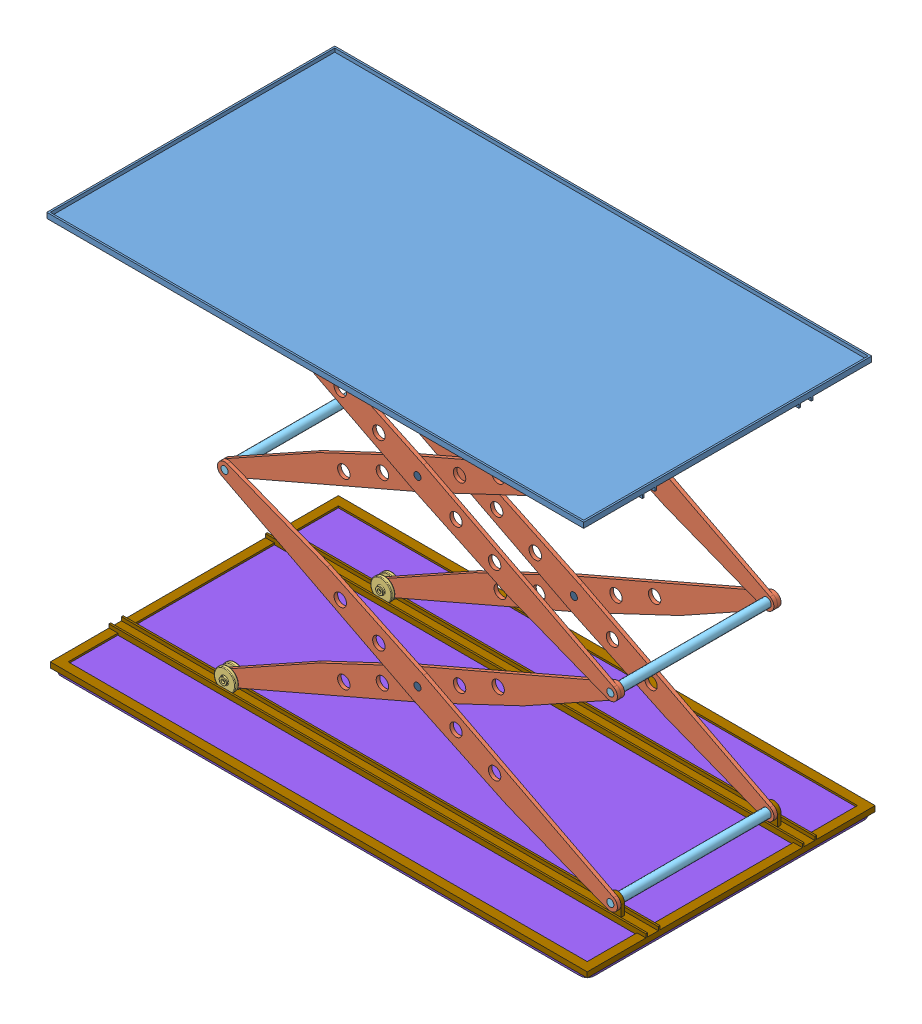
SolidWorks assembly Lift, configuration Default. Lengths in mm.
Overall size (1524.62 1125.01 820).
26 component instances, 10 part files, 62 mates.
Components (placement in the parent):
- Ground Frame-1: Ground Frame [Default] at (6.645 35.4607 -1636.1522) size (1510 70 810)
- Scissor Arm-1: Scissor Arm [Default] at (114.1185 -255.7912 -1846.1522) x (0.904211 0.427086 0) z (0 0 1) size (1240 80 10)
- Scissor Arm-3: Scissor Arm [Default] at (114.1185 -255.7912 -1426.1522) x (0.904211 0.427086 0) z (0 0 1) size (1240 80 10)
- Scissor Arm-4: Scissor Arm [Default] at (114.1185 -255.7912 -1856.1522) x (0.904211 -0.427086 0) z (0 0 1) size (1240 80 10)
- Scissor Arm-5: Scissor Arm [Default] at (114.1185 -255.7912 -1416.1522) x (0.904211 -0.427086 0) z (0 0 1) size (1240 80 10)
- Roller-1: Roller [Default] at (-428.408 0.4607 -1871.1522) x (-0.996904 0.078629 0) z (0 0 1) size (60 60 40)
- Roller-2: Roller [Default] at (-428.408 0.4607 -1431.1522) x (0.925109 -0.379702 0) z (0 0 1) size (60 60 40)
- Force Rod-2: Force Rod [Default] at (-428.408 0.4607 -1636.1522) x (0 0 1) z (-1 0 0) size (410 40 30)
- Scissor Arm-6: Scissor Arm [Default] at (114.1185 -768.2949 -1856.1522) x (0.904211 -0.427086 0) z (0 0 1) size (1240 80 10)
- Scissor Arm-7: Scissor Arm [Default] at (114.1185 -768.2949 -1416.1522) x (0.904211 -0.427086 0) z (0 0 1) size (1240 80 10)
- Scissor Arm-8: Scissor Arm [Default] at (114.1185 -768.2949 -1426.1522) x (0.904211 0.427086 0) z (0 0 1) size (1240 80 10)
- Scissor Arm-9: Scissor Arm [Default] at (114.1185 -768.2949 -1866.1522) x (0.904211 0.427086 0) z (0 0 1) size (1240 80 10)
- Center Rod-1: Center Rod [Default] at (656.645 -512.0431 -1641.1522) x (0 0 1) z (0.968151 -0.250368 0) size (460 25 25)
- Center Rod-2: Center Rod [Default] at (656.645 0.4607 -1641.1522) x (0 0 -1) z (0.999908 0.013578 0) size (460 25 25)
- Center Rod-3: Center Rod [Default] at (-428.408 -512.0431 -1641.1522) x (0 0 1) z (-0.996451 -0.084176 0) size (460 25 25)
- Lead Screw-1: Lead Screw [Default] at (-247.9541 0.4607 -1636.1522) x (1 0 0) z (0 -0.731326 0.682028) size (1030.02 30.61 26.52)
- Motor-1: Motor [Default] at (322.1358 0.4607 -1615.8755) x (0 0 1) z (-1 0 0) size (60 60 90)
- Platform-1: Platform [Default] at (6.645 -1069.5468 -1646.1522) size (1500 20 800)
- Frame-1: Frame [Default] at (6.645 -1059.5468 -1646.1522) x (1 0 0) z (0 0 -1) size (1510 65 810)
- Center Rod-4: Center Rod [Default] at (656.645 -1024.5468 -1641.1522) x (0 0 1) z (0.247233 0.968956 0) size (460 25 25)
- Roller-3: Roller [Default] at (-428.408 -1024.5468 -1881.1522) size (60 60 40)
- Roller-4: Roller [Default] at (-428.408 -1024.5468 -1441.1522) x (0.838333 0.545159 0) z (0 0 1) size (60 60 40)
- fixingCenter-1: fixingCenter [Default] at (114.1185 -255.7912 -1856.1522) x (0 0 -1) z (0.990959 0.134167 0) size (30 25 25)
- fixingCenter-2: fixingCenter [Default] at (114.1185 -255.7912 -1426.1522) x (0 0 -1) z (0.998189 0.060154 0) size (30 25 25)
- fixingCenter-3: fixingCenter [Default] at (114.1185 -768.2949 -1426.1522) x (0 0 -1) z (1 0 0) size (30 25 25)
- fixingCenter-4: fixingCenter [Default] at (114.1185 -768.2949 -1866.1522) x (0 0 -1) z (0.935797 0.352539 0) size (30 25 25)
Mates (geometry in assembly coordinates):
- Concentric1: concentric aligned: cylinder of Ground Frame-1 through (656.645 0.4607 -1851.1522) axis (0 0 -1) radius 10; cylinder of Scissor Arm-1 through (656.645 0.4607 -1841.1522) axis (0 0 -1) radius 10
- Coincident1: coincident anti-aligned: plane of Ground Frame-1 through (656.645 0.4607 -1851.1522) normal (0 0 1); plane of Scissor Arm-1 through (-428.408 -512.0431 -1851.1522) normal (0 0 -1)
- Concentric2: concentric aligned: cylinder of Ground Frame-1 through (656.645 0.4607 -1411.1522) axis (0 0 -1) radius 10; cylinder of Scissor Arm-3 through (656.645 0.4607 -1421.1522) axis (0 0 -1) radius 10
- Coincident2: coincident anti-aligned: plane of Ground Frame-1 through (656.645 0.4607 -1421.1522) normal (0 0 -1); plane of Scissor Arm-3 through (-428.408 -512.0431 -1421.1522) normal (0 0 1)
- Concentric3: concentric aligned: cylinder of Scissor Arm-1 through (114.1185 -255.7912 -1841.1522) axis (0 0 -1) radius 10; cylinder of Scissor Arm-4 through (114.1185 -255.7912 -1851.1522) axis (0 0 -1) radius 10
- Coincident3: coincident anti-aligned: plane of Scissor Arm-1 through (-428.408 -512.0431 -1851.1522) normal (0 0 -1); plane of Scissor Arm-4 through (-428.408 0.4607 -1851.1522) normal (0 0 1)
- Concentric4: concentric aligned: cylinder of Scissor Arm-3 through (114.1185 -255.7912 -1421.1522) axis (0 0 -1) radius 10; cylinder of Scissor Arm-5 through (114.1185 -255.7912 -1411.1522) axis (0 0 -1) radius 10
- Coincident4: coincident anti-aligned: plane of Scissor Arm-3 through (-428.408 -512.0431 -1421.1522) normal (0 0 1); plane of Scissor Arm-5 through (-428.408 0.4607 -1421.1522) normal (0 0 -1)
- Concentric5: concentric aligned: cylinder of Scissor Arm-4 through (-428.408 0.4607 -1851.1522) axis (0 0 -1) radius 10; cylinder of Roller-1 through (-428.408 0.4607 -1851.1522) axis (0 0 -1) radius 5
- Tangent1: tangent anti-aligned: plane of Ground Frame-1 through (6.645 30.4607 -1636.1522) normal (0 -1 0); cylinder of Roller-1 through (-428.408 0.4607 -1841.1522) axis (0 0 -1) radius 30
- Concentric6: concentric aligned: cylinder of Scissor Arm-5 through (-428.408 0.4607 -1411.1522) axis (0 0 -1) radius 10; cylinder of Roller-2 through (-428.408 0.4607 -1411.1522) axis (0 0 -1) radius 5
- Tangent2: tangent anti-aligned: plane of Ground Frame-1 through (6.645 30.4607 -1636.1522) normal (0 -1 0); cylinder of Roller-2 through (-428.408 0.4607 -1401.1522) axis (0 0 -1) radius 30
- Coincident7: coincident anti-aligned: plane of Ground Frame-1 through (-748.355 20.4607 -1431.1522) normal (0 0 1); plane of Roller-2 through (-428.408 0.4607 -1431.1522) normal (0 0 -1)
- Coincident8: coincident anti-aligned: plane of Ground Frame-1 through (761.645 20.4607 -1841.1522) normal (0 0 -1); plane of Roller-1 through (-428.408 0.4607 -1841.1522) normal (0 0 1)
- Concentric7: concentric anti-aligned: cylinder of Roller-2 through (-428.408 0.4607 -1436.1522) axis (0 0 1) radius 5; cylinder of Force Rod-2 through (-428.408 0.4607 -1836.1522) axis (0 0 -1) radius 5
- Concentric8: concentric anti-aligned: cylinder of Roller-1 through (-428.408 0.4607 -1836.1522) axis (0 0 -1) radius 5; cylinder of Force Rod-2 through (-428.408 0.4607 -1436.1522) axis (0 0 1) radius 5
- Coincident9: coincident anti-aligned: plane of Roller-2 through (-428.408 0.4607 -1436.1522) normal (0 0 -1); plane of Force Rod-2 through (-428.408 0.4607 -1436.1522) normal (0 0 1)
- Concentric9: concentric aligned: cylinder of Scissor Arm-1 through (-428.408 -512.0431 -1841.1522) axis (0 0 -1) radius 10; cylinder of Scissor Arm-6 through (-428.408 -512.0431 -1851.1522) axis (0 0 -1) radius 10
- Coincident10: coincident anti-aligned: plane of Scissor Arm-1 through (-428.408 -512.0431 -1851.1522) normal (0 0 -1); plane of Scissor Arm-6 through (-428.408 -512.0431 -1851.1522) normal (0 0 1)
- Concentric10: concentric aligned: cylinder of Scissor Arm-3 through (-428.408 -512.0431 -1421.1522) axis (0 0 -1) radius 10; cylinder of Scissor Arm-7 through (-428.408 -512.0431 -1411.1522) axis (0 0 -1) radius 10
- Coincident11: coincident anti-aligned: plane of Scissor Arm-7 through (-428.408 -512.0431 -1421.1522) normal (0 0 -1); plane of Scissor Arm-3 through (-428.408 -512.0431 -1421.1522) normal (0 0 1)
- Concentric11: concentric aligned: cylinder of Scissor Arm-5 through (656.645 -512.0431 -1411.1522) axis (0 0 -1) radius 10; cylinder of Scissor Arm-8 through (656.645 -512.0431 -1421.1522) axis (0 0 -1) radius 10
- Coincident12: coincident anti-aligned: plane of Scissor Arm-5 through (-428.408 0.4607 -1421.1522) normal (0 0 -1); plane of Scissor Arm-8 through (-428.408 -1024.5468 -1421.1522) normal (0 0 1)
- Concentric12: concentric aligned: cylinder of Scissor Arm-4 through (656.645 -512.0431 -1851.1522) axis (0 0 -1) radius 10; cylinder of Scissor Arm-9 through (656.645 -512.0431 -1861.1522) axis (0 0 -1) radius 10
- Concentric13: concentric anti-aligned: cylinder of Scissor Arm-9 through (656.645 -512.0431 -1861.1522) axis (0 0 -1) radius 10; cylinder of Center Rod-1 through (656.645 -512.0431 -1431.1522) axis (0 0 1) radius 10
- Concentric14: concentric aligned: cylinder of Scissor Arm-8 through (656.645 -512.0431 -1421.1522) axis (0 0 -1) radius 10; cylinder of Center Rod-1 through (656.645 -512.0431 -1851.1522) axis (0 0 -1) radius 10
- Coincident14: coincident anti-aligned: plane of Scissor Arm-8 through (-428.408 -1024.5468 -1431.1522) normal (0 0 -1); plane of Center Rod-1 through (656.645 -512.0431 -1431.1522) normal (0 0 1)
- Concentric15: concentric aligned: cylinder of Scissor Arm-1 through (656.645 0.4607 -1841.1522) axis (0 0 -1) radius 10; cylinder of Center Rod-2 through (656.645 0.4607 -1851.1522) axis (0 0 -1) radius 10
- Coincident15: coincident anti-aligned: plane of Scissor Arm-3 through (-428.408 -512.0431 -1431.1522) normal (0 0 -1); plane of Center Rod-2 through (656.645 0.4607 -1431.1522) normal (0 0 1)
- Concentric20: concentric anti-aligned: cylinder of Scissor Arm-3 through (-428.408 -512.0431 -1421.1522) axis (0 0 -1) radius 10; cylinder of Center Rod-3 through (-428.408 -512.0431 -1431.1522) axis (0 0 1) radius 10
- Coincident17: coincident anti-aligned: plane of Scissor Arm-3 through (-428.408 -512.0431 -1431.1522) normal (0 0 -1); plane of Center Rod-3 through (-428.408 -512.0431 -1431.1522) normal (0 0 1)
- Concentric21: concentric anti-aligned: cylinder of Ground Frame-1 through (234.145 0.4607 -1636.1522) axis (1 0 0) radius 10; cylinder of Lead Screw-1 through (267.0459 0.4607 -1636.1522) axis (-1 0 0) radius 10
- Coincident18: coincident anti-aligned: plane of Ground Frame-1 through (6.645 30.4607 -1636.1522) normal (0 -1 0); plane of Motor-1 through (292.1358 30.4607 -1645.8755) normal (0 1 0)
- Parallel1: parallel anti-aligned: cylinder of Lead Screw-1 through (267.0459 0.4607 -1636.1522) axis (-1 0 0) radius 10; cylinder of Motor-1 through (262.1358 0.4607 -1615.8755) axis (1 0 0) radius 10
- Concentric25: concentric aligned: cylinder of Scissor Arm-6 through (114.1185 -768.2949 -1851.1522) axis (0 0 -1) radius 10; cylinder of Scissor Arm-9 through (114.1185 -768.2949 -1861.1522) axis (0 0 -1) radius 10
- Concentric26: concentric aligned: cylinder of Scissor Arm-7 through (114.1185 -768.2949 -1411.1522) axis (0 0 -1) radius 10; cylinder of Scissor Arm-8 through (114.1185 -768.2949 -1421.1522) axis (0 0 -1) radius 10
- Coincident19: coincident anti-aligned: plane of Platform-1 through (6.645 -1059.5468 -1646.1522) normal (0 1 0); plane of Frame-1 through (6.645 -1059.5468 -1646.1522) normal (0 -1 0)
- Parallel3: parallel aligned: plane of Platform-1 through (-743.355 -1059.5468 -1246.1522) normal (0 0 1); plane of Frame-1 through (-748.355 -1069.5468 -1241.1522) normal (0 0 1)
- Concentric28: concentric anti-aligned: cylinder of Scissor Arm-7 through (656.645 -1024.5468 -1411.1522) axis (0 0 -1) radius 10; cylinder of Frame-1 through (656.645 -1024.5468 -1431.1522) axis (0 0 1) radius 10
- Concentric29: concentric anti-aligned: cylinder of Scissor Arm-6 through (656.645 -1024.5468 -1851.1522) axis (0 0 -1) radius 10; cylinder of Frame-1 through (656.645 -1024.5468 -1871.1522) axis (0 0 1) radius 10
- Coincident21: coincident anti-aligned: plane of Scissor Arm-6 through (-428.408 -512.0431 -1861.1522) normal (0 0 -1); plane of Frame-1 through (656.645 -1024.5468 -1861.1522) normal (0 0 1)
- Coincident23: coincident anti-aligned: plane of Platform-1 through (756.645 -1059.5468 -2046.1522) normal (1 0 0); plane of Frame-1 through (756.645 -1069.5468 -1246.1522) normal (-1 0 0)
- Coincident24: coincident anti-aligned: plane of Platform-1 through (-743.355 -1059.5468 -2046.1522) normal (0 0 -1); plane of Frame-1 through (-743.355 -1069.5468 -2046.1522) normal (0 0 1)
- Concentric30: concentric anti-aligned: cylinder of Scissor Arm-6 through (656.645 -1024.5468 -1851.1522) axis (0 0 -1) radius 10; cylinder of Center Rod-4 through (656.645 -1024.5468 -1431.1522) axis (0 0 1) radius 10
- Concentric31: concentric anti-aligned: cylinder of Frame-1 through (656.645 -1024.5468 -1431.1522) axis (0 0 1) radius 10; cylinder of Center Rod-4 through (656.645 -1024.5468 -1851.1522) axis (0 0 -1) radius 10
- Coincident25: coincident anti-aligned: plane of Frame-1 through (656.645 -1024.5468 -1431.1522) normal (0 0 -1); plane of Center Rod-4 through (656.645 -1024.5468 -1431.1522) normal (0 0 1)
- Tangent3: tangent anti-aligned: plane of Frame-1 through (6.645 -1054.5468 -1646.1522) normal (0 1 0); cylinder of Roller-3 through (-428.408 -1024.5468 -1851.1522) axis (0 0 -1) radius 30
- Coincident26: coincident anti-aligned: plane of Frame-1 through (-748.355 -1044.5468 -1851.1522) normal (0 0 -1); plane of Roller-3 through (-428.408 -1024.5468 -1851.1522) normal (0 0 1)
- Tangent4: tangent anti-aligned: plane of Frame-1 through (6.645 -1054.5468 -1646.1522) normal (0 1 0); cylinder of Roller-4 through (-428.408 -1024.5468 -1431.1522) axis (0 0 -1) radius 30
- Coincident27: coincident anti-aligned: plane of Frame-1 through (761.645 -1044.5468 -1441.1522) normal (0 0 1); plane of Roller-4 through (-428.408 -1024.5468 -1441.1522) normal (0 0 -1)
- Concentric32: concentric aligned: cylinder of Scissor Arm-9 through (-428.408 -1024.5468 -1861.1522) axis (0 0 -1) radius 10; cylinder of Roller-3 through (-428.408 -1024.5468 -1861.1522) axis (0 0 -1) radius 5
- Concentric33: concentric aligned: cylinder of Scissor Arm-8 through (-428.408 -1024.5468 -1421.1522) axis (0 0 -1) radius 10; cylinder of Roller-4 through (-428.408 -1024.5468 -1421.1522) axis (0 0 -1) radius 5
- Coincident28: coincident anti-aligned: plane of Scissor Arm-4 through (-428.408 0.4607 -1861.1522) normal (0 0 -1); plane of Scissor Arm-9 through (-428.408 -1024.5468 -1861.1522) normal (0 0 1)
- Concentric34: concentric aligned: cylinder of Force Rod-2 through (-413.408 0.4607 -1636.1522) axis (-1 0 0) radius 9; cylinder of Lead Screw-1 through (267.0459 0.4607 -1636.1522) axis (-1 0 0) radius 10
- Concentric35: concentric anti-aligned: cylinder of Scissor Arm-4 through (114.1185 -255.7912 -1851.1522) axis (0 0 -1) radius 10; cylinder of fixingCenter-1 through (114.1185 -255.7912 -1851.1522) axis (0 0 1) radius 10
- Coincident29: coincident aligned: plane of Scissor Arm-4 through (-428.408 0.4607 -1861.1522) normal (0 0 -1); plane of fixingCenter-1 through (114.1185 -255.7912 -1861.1522) normal (0 0 -1)
- Concentric36: concentric anti-aligned: cylinder of Scissor Arm-5 through (114.1185 -255.7912 -1411.1522) axis (0 0 -1) radius 10; cylinder of fixingCenter-2 through (114.1185 -255.7912 -1421.1522) axis (0 0 1) radius 10
- Coincident30: coincident aligned: plane of Scissor Arm-3 through (-428.408 -512.0431 -1431.1522) normal (0 0 -1); plane of fixingCenter-2 through (114.1185 -255.7912 -1431.1522) normal (0 0 -1)
- Concentric37: concentric anti-aligned: cylinder of Scissor Arm-8 through (114.1185 -768.2949 -1421.1522) axis (0 0 -1) radius 10; cylinder of fixingCenter-3 through (114.1185 -768.2949 -1421.1522) axis (0 0 1) radius 10
- Coincident31: coincident aligned: plane of Scissor Arm-8 through (-428.408 -1024.5468 -1431.1522) normal (0 0 -1); plane of fixingCenter-3 through (114.1185 -768.2949 -1431.1522) normal (0 0 -1)
- Concentric38: concentric anti-aligned: cylinder of Scissor Arm-9 through (114.1185 -768.2949 -1861.1522) axis (0 0 -1) radius 10; cylinder of fixingCenter-4 through (114.1185 -768.2949 -1861.1522) axis (0 0 1) radius 10
- Coincident32: coincident aligned: plane of Scissor Arm-9 through (-428.408 -1024.5468 -1871.1522) normal (0 0 -1); plane of fixingCenter-4 through (114.1185 -768.2949 -1871.1522) normal (0 0 -1)
